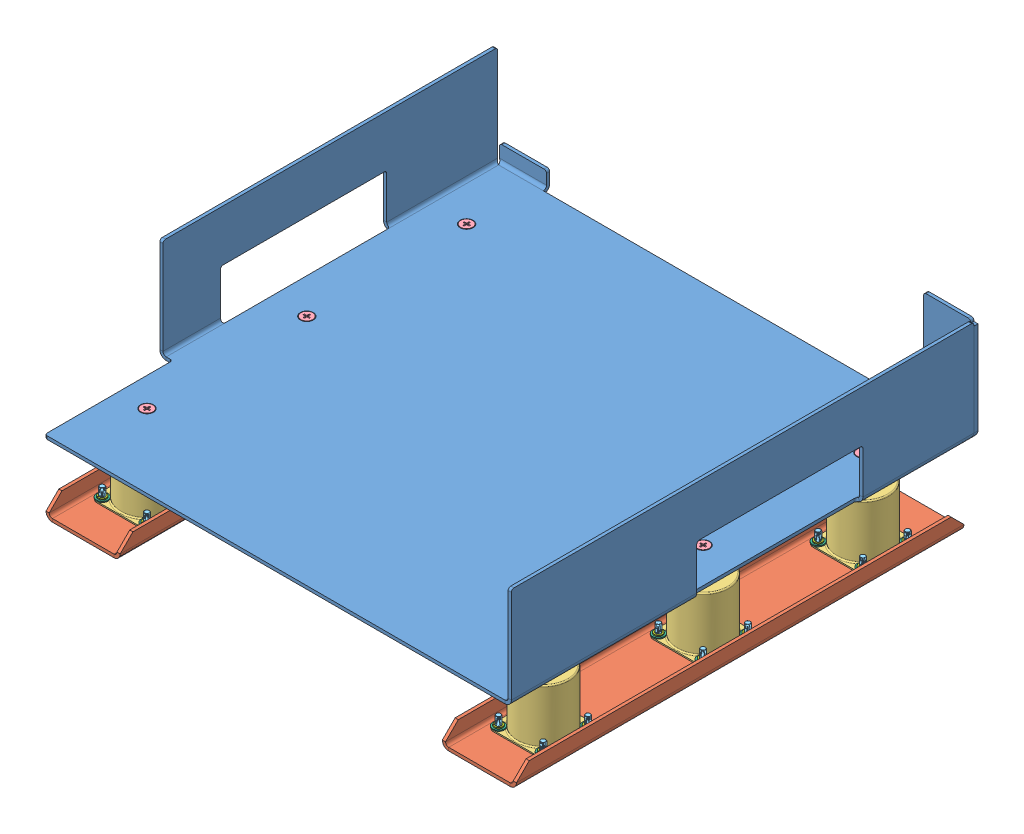
SolidWorks assembly Сборка, configuration По умолчанию. Lengths in mm.
Overall size (375.45 141.9 365.44).
87 component instances, 7 part files, 155 mates.
Components (placement in the parent):
- 1_Полка-1: 1_Полка [По умолчанию<Как обработанный>] at (-182.6691 43.1061 558.1681) size (375.45 80.44 365.44)
- 2_Основание-1: 2_Основание [По умолчанию] at (-150.1691 -18.3939 375.6681) x (0 0 -1) z (1 0 0) size (350 15 58)
- 2_Основание-2: 2_Основание [По умолчанию] at (159.8309 -18.3939 375.6681) x (0 0 1) z (-1 0 0) size (350 15 58)
- 8_Амортизатор-1: 8_Амортизатор [По умолчанию] at (-150.1691 -17.3939 500.6681) size (44 59 44)
- 8_Амортизатор-2: 8_Амортизатор [По умолчанию] at (-150.1691 -17.3939 375.6681) size (44 59 44)
- 8_Амортизатор-3: 8_Амортизатор [По умолчанию] at (159.8309 -17.3939 375.6681) size (44 59 44)
- 8_Амортизатор-4: 8_Амортизатор [По умолчанию] at (159.8309 -17.3939 250.6681) size (44 59 44)
- 8_Амортизатор-5: 8_Амортизатор [По умолчанию] at (159.8309 -17.3939 500.6681) size (44 59 44)
- 8_Амортизатор-6: 8_Амортизатор [По умолчанию] at (-150.1691 -17.3939 250.6681) size (44 59 44)
- 7_Винт_М5-1: 7_Винт_М5 [По умолчанию] at (159.8309 31.2061 250.6681) size (9.3 12.3 9.3)
- 7_Винт_М5-2: 7_Винт_М5 [По умолчанию] at (159.8309 31.2061 500.6681) size (9.3 12.3 9.3)
- 7_Винт_М5-3: 7_Винт_М5 [По умолчанию] at (159.8309 31.2061 375.6681) size (9.3 12.3 9.3)
- 7_Винт_М5-4: 7_Винт_М5 [По умолчанию] at (-150.1691 31.2061 500.6681) size (9.3 12.3 9.3)
- 7_Винт_М5-5: 7_Винт_М5 [По умолчанию] at (-150.1691 31.2061 375.6681) size (9.3 12.3 9.3)
- 7_Винт_М5-6: 7_Винт_М5 [По умолчанию] at (-150.1691 31.2061 250.6681) size (9.3 12.3 9.3)
- 6_Винт_М4-1: 6_Винт_М4 [По умолчанию] at (-132.6691 -9.2939 358.1681) x (1 0 0) z (0 0 -1) size (8.4 12.23 8.4)
- 6_Винт_М4-2: 6_Винт_М4 [По умолчанию] at (-132.6691 -9.2939 393.1681) x (1 0 0) z (0 0 -1) size (8.4 12.23 8.4)
- 6_Винт_М4-3: 6_Винт_М4 [По умолчанию] at (-132.6691 -9.2939 268.1681) x (1 0 0) z (0 0 -1) size (8.4 12.23 8.4)
- 6_Винт_М4-4: 6_Винт_М4 [По умолчанию] at (-132.6691 -9.2939 233.1681) x (1 0 0) z (0 0 -1) size (8.4 12.23 8.4)
- 6_Винт_М4-5: 6_Винт_М4 [По умолчанию] at (-167.6691 -9.2939 268.1681) x (1 0 0) z (0 0 -1) size (8.4 12.23 8.4)
- 6_Винт_М4-6: 6_Винт_М4 [По умолчанию] at (-167.6691 -9.2939 233.1681) x (1 0 0) z (0 0 -1) size (8.4 12.23 8.4)
- 6_Винт_М4-7: 6_Винт_М4 [По умолчанию] at (-167.6691 -9.2939 358.1681) x (1 0 0) z (0 0 -1) size (8.4 12.23 8.4)
- 6_Винт_М4-8: 6_Винт_М4 [По умолчанию] at (-167.6691 -9.2939 393.1681) x (1 0 0) z (0 0 -1) size (8.4 12.23 8.4)
- 6_Винт_М4-9: 6_Винт_М4 [По умолчанию] at (-132.6691 -9.2939 483.1681) x (1 0 0) z (0 0 -1) size (8.4 12.23 8.4)
- 6_Винт_М4-10: 6_Винт_М4 [По умолчанию] at (-167.6691 -9.2939 483.1681) x (1 0 0) z (0 0 -1) size (8.4 12.23 8.4)
- 6_Винт_М4-11: 6_Винт_М4 [По умолчанию] at (-132.6691 -9.2939 518.1681) x (1 0 0) z (0 0 -1) size (8.4 12.23 8.4)
- 6_Винт_М4-12: 6_Винт_М4 [По умолчанию] at (-167.6691 -9.2939 518.1681) x (1 0 0) z (0 0 -1) size (8.4 12.23 8.4)
- 6_Винт_М4-13: 6_Винт_М4 [По умолчанию] at (142.3309 -9.2939 393.1681) x (1 0 0) z (0 0 -1) size (8.4 12.23 8.4)
- 6_Винт_М4-14: 6_Винт_М4 [По умолчанию] at (177.3309 -9.2939 393.1681) x (1 0 0) z (0 0 -1) size (8.4 12.23 8.4)
- 6_Винт_М4-15: 6_Винт_М4 [По умолчанию] at (142.3309 -9.2939 358.1681) x (1 0 0) z (0 0 -1) size (8.4 12.23 8.4)
- 6_Винт_М4-16: 6_Винт_М4 [По умолчанию] at (177.3309 -9.2939 358.1681) x (1 0 0) z (0 0 -1) size (8.4 12.23 8.4)
- 6_Винт_М4-17: 6_Винт_М4 [По умолчанию] at (142.3309 -9.2939 268.1681) x (1 0 0) z (0 0 -1) size (8.4 12.23 8.4)
- 6_Винт_М4-18: 6_Винт_М4 [По умолчанию] at (177.3309 -9.2939 233.1681) x (1 0 0) z (0 0 -1) size (8.4 12.23 8.4)
- 6_Винт_М4-19: 6_Винт_М4 [По умолчанию] at (142.3309 -9.2939 233.1681) x (1 0 0) z (0 0 -1) size (8.4 12.23 8.4)
- 6_Винт_М4-20: 6_Винт_М4 [По умолчанию] at (177.3309 -9.2939 268.1681) x (1 0 0) z (0 0 -1) size (8.4 12.23 8.4)
- 6_Винт_М4-21: 6_Винт_М4 [По умолчанию] at (142.3309 -9.2939 483.1681) x (1 0 0) z (0 0 -1) size (8.4 12.23 8.4)
- 6_Винт_М4-22: 6_Винт_М4 [По умолчанию] at (142.3309 -9.2939 518.1681) x (1 0 0) z (0 0 -1) size (8.4 12.23 8.4)
- 6_Винт_М4-23: 6_Винт_М4 [По умолчанию] at (177.3309 -9.2939 518.1681) x (1 0 0) z (0 0 -1) size (8.4 12.23 8.4)
- 6_Винт_М4-24: 6_Винт_М4 [По умолчанию] at (177.3309 -9.2939 483.1681) x (1 0 0) z (0 0 -1) size (8.4 12.23 8.4)
- 5_Шайба_А4-1: 5_Шайба_А4 [По умолчанию] at (-167.6691 -17.3939 483.1681) size (9 0.8 9)
- 5_Шайба_А4-2: 5_Шайба_А4 [По умолчанию] at (-167.6691 -17.3939 518.1681) size (9 0.8 9)
- 5_Шайба_А4-3: 5_Шайба_А4 [По умолчанию] at (-132.6691 -17.3939 483.1681) size (9 0.8 9)
- 5_Шайба_А4-4: 5_Шайба_А4 [По умолчанию] at (-132.6691 -17.3939 518.1681) size (9 0.8 9)
- 5_Шайба_А4-5: 5_Шайба_А4 [По умолчанию] at (-132.6691 -17.3939 358.1681) size (9 0.8 9)
- 5_Шайба_А4-6: 5_Шайба_А4 [По умолчанию] at (-167.6691 -17.3939 358.1681) x (0.667265 0 0.74482) z (-0.74482 0 0.667265) size (9 0.8 9)
- 5_Шайба_А4-7: 5_Шайба_А4 [По умолчанию] at (-132.6691 -17.3939 393.1681) size (9 0.8 9)
- 5_Шайба_А4-8: 5_Шайба_А4 [По умолчанию] at (-167.6691 -17.3939 393.1681) x (0.975059 0 0.221947) z (-0.221947 0 0.975059) size (9 0.8 9)
- 5_Шайба_А4-9: 5_Шайба_А4 [По умолчанию] at (-167.6691 -17.3939 268.1681) size (9 0.8 9)
- 5_Шайба_А4-10: 5_Шайба_А4 [По умолчанию] at (-132.6691 -17.3939 268.1681) size (9 0.8 9)
- 5_Шайба_А4-11: 5_Шайба_А4 [По умолчанию] at (-167.6691 -17.3939 233.1681) size (9 0.8 9)
- 5_Шайба_А4-12: 5_Шайба_А4 [По умолчанию] at (-132.6691 -17.3939 233.1681) size (9 0.8 9)
- 5_Шайба_А4-13: 5_Шайба_А4 [По умолчанию] at (142.3309 -17.3939 518.1681) size (9 0.8 9)
- 5_Шайба_А4-14: 5_Шайба_А4 [По умолчанию] at (142.3309 -17.3939 483.1681) size (9 0.8 9)
- 5_Шайба_А4-15: 5_Шайба_А4 [По умолчанию] at (177.3309 -17.3939 483.1681) size (9 0.8 9)
- 5_Шайба_А4-16: 5_Шайба_А4 [По умолчанию] at (177.3309 -17.3939 518.1681) size (9 0.8 9)
- 5_Шайба_А4-17: 5_Шайба_А4 [По умолчанию] at (142.3309 -17.3939 358.1681) size (9 0.8 9)
- 5_Шайба_А4-18: 5_Шайба_А4 [По умолчанию] at (177.3309 -17.3939 393.1681) size (9 0.8 9)
- 5_Шайба_А4-19: 5_Шайба_А4 [По умолчанию] at (142.3309 -17.3939 393.1681) size (9 0.8 9)
- 5_Шайба_А4-20: 5_Шайба_А4 [По умолчанию] at (177.3309 -17.3939 358.1681) size (9 0.8 9)
- 5_Шайба_А4-21: 5_Шайба_А4 [По умолчанию] at (142.3309 -17.3939 268.1681) size (9 0.8 9)
- 5_Шайба_А4-22: 5_Шайба_А4 [По умолчанию] at (142.3309 -17.3939 233.1681) size (9 0.8 9)
- 5_Шайба_А4-23: 5_Шайба_А4 [По умолчанию] at (177.3309 -17.3939 233.1681) size (9 0.8 9)
- 5_Шайба_А4-24: 5_Шайба_А4 [По умолчанию] at (177.3309 -17.3939 268.1681) size (9 0.8 9)
- 4_Шайба-1: 4_Шайба [По умолчанию] at (-132.6691 -16.5939 518.1681) x (-0.950092 0 -0.311971) z (0.311971 0 -0.950092) size (6.5 0.8 6.5)
- 4_Шайба-2: 4_Шайба [По умолчанию] at (-167.6691 -16.5939 518.1681) x (-0.964104 0 -0.265525) z (0.265525 0 -0.964104) size (6.5 0.8 6.5)
- 4_Шайба-3: 4_Шайба [По умолчанию] at (-167.6691 -16.5939 483.1681) x (-0.900004 0 -0.435881) z (0.435881 0 -0.900004) size (6.5 0.8 6.5)
- 4_Шайба-4: 4_Шайба [По умолчанию] at (-132.6691 -16.5939 483.1681) x (0.833959 0 0.551827) z (-0.551827 0 0.833959) size (6.5 0.8 6.5)
- 4_Шайба-5: 4_Шайба [По умолчанию] at (-167.6691 -16.5939 358.1681) x (0.466083 0 -0.884741) z (0.884741 0 0.466083) size (6.5 0.8 6.5)
- 4_Шайба-6: 4_Шайба [По умолчанию] at (-132.6691 -16.5939 358.1681) x (0.892908 0 0.450239) z (-0.450239 0 0.892908) size (6.5 0.8 6.5)
- 4_Шайба-7: 4_Шайба [По умолчанию] at (-167.6691 -16.5939 393.1681) x (-0.311106 0 -0.950375) z (0.950375 0 -0.311106) size (6.5 0.8 6.5)
- 4_Шайба-8: 4_Шайба [По умолчанию] at (-132.6691 -16.5939 393.1681) size (6.5 0.8 6.5)
- 4_Шайба-13: 4_Шайба [По умолчанию] at (-132.6691 -16.5939 233.1681) size (6.5 0.8 6.5)
- 4_Шайба-14: 4_Шайба [По умолчанию] at (-167.6691 -16.5939 268.1681) size (6.5 0.8 6.5)
- 4_Шайба-15: 4_Шайба [По умолчанию] at (-132.6691 -16.5939 268.1681) x (0.985052 0 -0.172259) z (0.172259 0 0.985052) size (6.5 0.8 6.5)
- 4_Шайба-16: 4_Шайба [По умолчанию] at (-167.6691 -16.5939 233.1681) size (6.5 0.8 6.5)
- 4_Шайба-17: 4_Шайба [По умолчанию] at (177.3309 -16.5939 518.1681) x (-0.952485 0 -0.304585) z (0.304585 0 -0.952485) size (6.5 0.8 6.5)
- 4_Шайба-19: 4_Шайба [По умолчанию] at (142.3309 -16.5939 518.1681) x (-0.742093 0 -0.670297) z (0.670297 0 -0.742093) size (6.5 0.8 6.5)
- 4_Шайба-20: 4_Шайба [По умолчанию] at (142.3309 -16.5939 483.1681) x (0.157887 0 -0.987457) z (0.987457 0 0.157887) size (6.5 0.8 6.5)
- 4_Шайба-21: 4_Шайба [По умолчанию] at (177.3309 -16.5939 483.1681) x (0.73951 0 0.673145) z (-0.673145 0 0.73951) size (6.5 0.8 6.5)
- 4_Шайба-22: 4_Шайба [По умолчанию] at (177.3309 -16.5939 233.1681) x (0.8131 0 0.582125) z (-0.582125 0 0.8131) size (6.5 0.8 6.5)
- 4_Шайба-23: 4_Шайба [По умолчанию] at (142.3309 -16.5939 233.1681) size (6.5 0.8 6.5)
- 4_Шайба-24: 4_Шайба [По умолчанию] at (142.3309 -16.5939 268.1681) size (6.5 0.8 6.5)
- 4_Шайба-25: 4_Шайба [По умолчанию] at (177.3309 -16.5939 268.1681) x (-0.997954 0 -0.063934) z (0.063934 0 -0.997954) size (6.5 0.8 6.5)
- 4_Шайба-26: 4_Шайба [По умолчанию] at (142.3309 -16.5939 358.1681) size (6.5 0.8 6.5)
- 4_Шайба-27: 4_Шайба [По умолчанию] at (142.3309 -16.5939 393.1681) size (6.5 0.8 6.5)
- 4_Шайба-28: 4_Шайба [По умолчанию] at (177.3309 -16.5939 358.1681) x (0.299403 0 0.954127) z (-0.954127 0 0.299403) size (6.5 0.8 6.5)
- 4_Шайба-29: 4_Шайба [По умолчанию] at (177.3309 -16.5939 393.1681) size (6.5 0.8 6.5)
Mates (geometry in assembly coordinates):
- Концентричный1: concentric aligned: circle of 1_Полка-1; circle of 8_Амортизатор-6
- Совпадение2: coincident anti-aligned: plane of 1_Полка-1 through (-182.6691 40.6061 558.1681) normal (0 -1 0); plane of 8_Амортизатор-6 through (-150.1691 40.6061 250.6681) normal (0 1 0)
- Совпадение3: coincident aligned: cone of 1_Полка-1 through (-150.1691 40.7561 250.6681) axis (0 -1 0); cone of 7_Винт_М5-6 through (-150.1691 42.6561 250.6681) axis (0 -1 0)
- Концентричный2: concentric aligned: circle of 1_Полка-1; circle of 8_Амортизатор-2
- Совпадение4: coincident anti-aligned: plane of 1_Полка-1 through (-182.6691 40.6061 558.1681) normal (0 -1 0); plane of 8_Амортизатор-2 through (-150.1691 40.6061 375.6681) normal (0 1 0)
- Концентричный3: concentric aligned: circle of 1_Полка-1; circle of 8_Амортизатор-1
- Совпадение5: coincident anti-aligned: plane of 1_Полка-1 through (-182.6691 40.6061 558.1681) normal (0 -1 0); plane of 8_Амортизатор-1 through (-150.1691 40.6061 500.6681) normal (0 1 0)
- Концентричный4: concentric aligned: circle of 1_Полка-1; circle of 8_Амортизатор-4
- Совпадение6: coincident anti-aligned: plane of 1_Полка-1 through (-182.6691 40.6061 558.1681) normal (0 -1 0); plane of 8_Амортизатор-4 through (159.8309 40.6061 250.6681) normal (0 1 0)
- Концентричный5: concentric aligned: circle of 1_Полка-1; circle of 8_Амортизатор-3
- Совпадение7: coincident anti-aligned: plane of 1_Полка-1 through (-182.6691 40.6061 558.1681) normal (0 -1 0); plane of 8_Амортизатор-3 through (159.8309 40.6061 375.6681) normal (0 1 0)
- Концентричный6: concentric aligned: circle of 1_Полка-1; circle of 8_Амортизатор-5
- Совпадение8: coincident anti-aligned: plane of 1_Полка-1 through (-182.6691 40.6061 558.1681) normal (0 -1 0); plane of 8_Амортизатор-5 through (159.8309 40.6061 500.6681) normal (0 1 0)
- Совпадение9: coincident aligned: cone of 1_Полка-1 through (-150.1691 40.7561 375.6681) axis (0 -1 0); cone of 7_Винт_М5-5 through (-150.1691 42.6561 375.6681) axis (0 -1 0)
- Совпадение10: coincident aligned: cone of 1_Полка-1 through (-150.1691 40.7561 500.6681) axis (0 -1 0); cone of 7_Винт_М5-4 through (-150.1691 42.6561 500.6681) axis (0 -1 0)
- Совпадение11: coincident aligned: cone of 1_Полка-1 through (159.8309 40.7561 500.6681) axis (0 -1 0); cone of 7_Винт_М5-2 through (159.8309 42.6561 500.6681) axis (0 -1 0)
- Совпадение12: coincident aligned: cone of 1_Полка-1 through (159.8309 40.7561 375.6681) axis (0 -1 0); cone of 7_Винт_М5-3 through (159.8309 42.6561 375.6681) axis (0 -1 0)
- Совпадение14: coincident aligned: cone of 1_Полка-1 through (159.8309 40.7561 250.6681) axis (0 -1 0); cone of 7_Винт_М5-1 through (159.8309 42.6561 250.6681) axis (0 -1 0)
- Концентричный11: concentric aligned: circle of 2_Основание-1; circle of 8_Амортизатор-6
- Концентричный12: concentric aligned: circle of 2_Основание-1; circle of 8_Амортизатор-6
- Концентричный13: concentric aligned: circle of 2_Основание-1; circle of 8_Амортизатор-2
- Концентричный14: concentric anti-aligned: cylinder of 2_Основание-1; cylinder of 8_Амортизатор-2 through (-132.6691 24.8061 393.1681) axis (0 -1 0) radius 2
- Концентричный15: concentric anti-aligned: circle of 2_Основание-1; cylinder of 8_Амортизатор-1 through (-167.6691 24.8061 483.1681) axis (0 -1 0) radius 2
- Концентричный16: concentric aligned: circle of 2_Основание-1; circle of 8_Амортизатор-1
- Совпадение15: coincident anti-aligned: plane of 2_Основание-1 through (-150.1691 -18.3939 375.6681) normal (0 1 0); plane of 8_Амортизатор-1 through (-150.1691 -18.3939 500.6681) normal (0 -1 0)
- Совпадение16: coincident aligned: cone of 2_Основание-1 through (-167.6691 -20.8939 518.1681) axis (0 1 0); cone of 6_Винт_М4-12 through (-167.6691 -20.7939 518.1681) axis (0 1 0)
- Совпадение17: coincident aligned: cone of 2_Основание-1 through (-132.6691 -20.8939 518.1681) axis (0 1 0); cone of 6_Винт_М4-11 through (-132.6691 -20.7939 518.1681) axis (0 1 0)
- Совпадение18: coincident anti-aligned: cone of 2_Основание-1 through (-167.6691 -20.8939 483.1681) axis (0 1 0); circle of 6_Винт_М4-10
- Совпадение19: coincident anti-aligned: cone of 2_Основание-1 through (-132.6691 -20.8939 483.1681) axis (0 1 0); circle of 6_Винт_М4-9
- Совпадение20: coincident aligned: cone of 2_Основание-1 through (-167.6691 -20.8939 393.1681) axis (0 1 0); cone of 6_Винт_М4-8 through (-167.6691 -20.7939 393.1681) axis (0 1 0)
- Совпадение21: coincident aligned: cone of 2_Основание-1 through (-132.6691 -20.8939 358.1681) axis (0 1 0); cone of 6_Винт_М4-1 through (-132.6691 -20.7939 358.1681) axis (0 1 0)
- Совпадение22: coincident aligned: cone of 2_Основание-1 through (-167.6691 -20.8939 358.1681) axis (0 1 0); cone of 6_Винт_М4-7 through (-167.6691 -20.7939 358.1681) axis (0 1 0)
- Совпадение23: coincident aligned: cone of 2_Основание-1 through (-132.6691 -20.8939 393.1681) axis (0 1 0); cone of 6_Винт_М4-2 through (-132.6691 -20.7939 393.1681) axis (0 1 0)
- Совпадение24: coincident aligned: cone of 2_Основание-1 through (-167.6691 -20.8939 268.1681) axis (0 1 0); cone of 6_Винт_М4-5 through (-167.6691 -20.7939 268.1681) axis (0 1 0)
- Совпадение25: coincident aligned: cone of 2_Основание-1 through (-167.6691 -20.8939 233.1681) axis (0 1 0); cone of 6_Винт_М4-6 through (-167.6691 -20.7939 233.1681) axis (0 1 0)
- Совпадение26: coincident aligned: cone of 2_Основание-1 through (-132.6691 -20.8939 233.1681) axis (0 1 0); cone of 6_Винт_М4-4 through (-132.6691 -20.7939 233.1681) axis (0 1 0)
- Совпадение27: coincident aligned: cone of 2_Основание-1 through (-132.6691 -20.8939 268.1681) axis (0 1 0); cone of 6_Винт_М4-3 through (-132.6691 -20.7939 268.1681) axis (0 1 0)
- Концентричный17: concentric anti-aligned: circle of 2_Основание-2; cylinder of 8_Амортизатор-5 through (142.3309 24.8061 483.1681) axis (0 -1 0) radius 2
- Концентричный18: concentric anti-aligned: circle of 2_Основание-2; cylinder of 8_Амортизатор-5 through (177.3309 24.8061 518.1681) axis (0 -1 0) radius 2
- Концентричный19: concentric anti-aligned: circle of 2_Основание-2; cylinder of 8_Амортизатор-3 through (142.3309 24.8061 393.1681) axis (0 -1 0) radius 2
- Концентричный20: concentric aligned: circle of 2_Основание-2; circle of 8_Амортизатор-3
- Концентричный21: concentric anti-aligned: circle of 2_Основание-2; cylinder of 8_Амортизатор-4 through (142.3309 24.8061 268.1681) axis (0 -1 0) radius 2
- Концентричный22: concentric anti-aligned: circle of 2_Основание-2; cylinder of 8_Амортизатор-4 through (177.3309 24.8061 233.1681) axis (0 -1 0) radius 2
- Совпадение28: coincident anti-aligned: plane of 2_Основание-2 through (159.8309 -18.3939 375.6681) normal (0 1 0); plane of 8_Амортизатор-5 through (159.8309 -18.3939 500.6681) normal (0 -1 0)
- Совпадение29: coincident aligned: cone of 2_Основание-2 through (142.3309 -20.8939 518.1681) axis (0 1 0); cone of 6_Винт_М4-22 through (142.3309 -20.7939 518.1681) axis (0 1 0)
- Совпадение30: coincident aligned: cone of 2_Основание-2 through (177.3309 -20.8939 518.1681) axis (0 1 0); cone of 6_Винт_М4-23 through (177.3309 -20.7939 518.1681) axis (0 1 0)
- Совпадение31: coincident aligned: cone of 2_Основание-2 through (142.3309 -20.8939 483.1681) axis (0 1 0); cone of 6_Винт_М4-21 through (142.3309 -20.7939 483.1681) axis (0 1 0)
- Совпадение32: coincident aligned: cone of 2_Основание-2 through (177.3309 -20.8939 483.1681) axis (0 1 0); cone of 6_Винт_М4-24 through (177.3309 -20.7939 483.1681) axis (0 1 0)
- Совпадение33: coincident aligned: cone of 2_Основание-2 through (142.3309 -20.8939 393.1681) axis (0 1 0); cone of 6_Винт_М4-13 through (142.3309 -20.7939 393.1681) axis (0 1 0)
- Совпадение34: coincident aligned: cone of 2_Основание-2 through (177.3309 -20.8939 393.1681) axis (0 1 0); cone of 6_Винт_М4-14 through (177.3309 -20.7939 393.1681) axis (0 1 0)
- Совпадение35: coincident aligned: cone of 2_Основание-2 through (142.3309 -20.8939 358.1681) axis (0 1 0); cone of 6_Винт_М4-15 through (142.3309 -20.7939 358.1681) axis (0 1 0)
- Совпадение36: coincident aligned: cone of 2_Основание-2 through (177.3309 -20.8939 358.1681) axis (0 1 0); cone of 6_Винт_М4-16 through (177.3309 -20.7939 358.1681) axis (0 1 0)
- Совпадение37: coincident aligned: cone of 2_Основание-2 through (142.3309 -20.8939 268.1681) axis (0 1 0); cone of 6_Винт_М4-17 through (142.3309 -20.7939 268.1681) axis (0 1 0)
- Совпадение38: coincident aligned: cone of 2_Основание-2 through (177.3309 -20.8939 233.1681) axis (0 1 0); cone of 6_Винт_М4-18 through (177.3309 -20.7939 233.1681) axis (0 1 0)
- Совпадение39: coincident aligned: cone of 2_Основание-2 through (177.3309 -20.8939 268.1681) axis (0 1 0); cone of 6_Винт_М4-20 through (177.3309 -20.7939 268.1681) axis (0 1 0)
- Совпадение40: coincident aligned: cone of 2_Основание-2 through (142.3309 -20.8939 233.1681) axis (0 1 0); cone of 6_Винт_М4-19 through (142.3309 -20.7939 233.1681) axis (0 1 0)
- Совпадение43: coincident anti-aligned: plane of 8_Амортизатор-1 through (-150.1691 -17.3939 500.6681) normal (0 1 0); plane of 5_Шайба_А4-2 through (-167.6691 -17.3939 518.1681) normal (0 -1 0)
- Концентричный24: concentric aligned: circle of 8_Амортизатор-1; circle of 5_Шайба_А4-2
- Совпадение44: coincident anti-aligned: plane of 8_Амортизатор-1 through (-150.1691 -17.3939 500.6681) normal (0 1 0); plane of 5_Шайба_А4-4 through (-132.6691 -17.3939 518.1681) normal (0 -1 0)
- Концентричный25: concentric aligned: circle of 8_Амортизатор-1; circle of 5_Шайба_А4-4
- Совпадение45: coincident anti-aligned: plane of 8_Амортизатор-1 through (-150.1691 -17.3939 500.6681) normal (0 1 0); plane of 5_Шайба_А4-1 through (-167.6691 -17.3939 483.1681) normal (0 -1 0)
- Концентричный26: concentric aligned: circle of 8_Амортизатор-1; circle of 5_Шайба_А4-1
- Совпадение46: coincident aligned: plane of 8_Амортизатор-1 through (-150.1691 -17.3939 500.6681) normal (0 1 0); circle of 5_Шайба_А4-3
- Концентричный27: concentric aligned: circle of 8_Амортизатор-1; circle of 5_Шайба_А4-3
- Концентричный28: concentric aligned: circle of 8_Амортизатор-2; circle of 5_Шайба_А4-7
- Совпадение47: coincident anti-aligned: plane of 8_Амортизатор-2 through (-150.1691 -17.3939 375.6681) normal (0 1 0); plane of 5_Шайба_А4-7 through (-132.6691 -17.3939 393.1681) normal (0 -1 0)
- Концентричный29: concentric aligned: circle of 8_Амортизатор-2; circle of 5_Шайба_А4-8
- Совпадение49: coincident anti-aligned: plane of 8_Амортизатор-2 through (-150.1691 -17.3939 375.6681) normal (0 1 0); plane of 5_Шайба_А4-8 through (-167.6691 -17.3939 393.1681) normal (0 -1 0)
- Концентричный30: concentric aligned: circle of 8_Амортизатор-2; circle of 5_Шайба_А4-6
- Совпадение51: coincident anti-aligned: plane of 8_Амортизатор-2 through (-150.1691 -17.3939 375.6681) normal (0 1 0); plane of 5_Шайба_А4-6 through (-167.6691 -17.3939 358.1681) normal (0 -1 0)
- Концентричный31: concentric aligned: circle of 8_Амортизатор-2; circle of 5_Шайба_А4-5
- Совпадение54: coincident anti-aligned: plane of 8_Амортизатор-2 through (-150.1691 -17.3939 375.6681) normal (0 1 0); plane of 5_Шайба_А4-5 through (-132.6691 -17.3939 358.1681) normal (0 -1 0)
- Концентричный32: concentric aligned: circle of 8_Амортизатор-6; circle of 5_Шайба_А4-9
- Совпадение55: coincident anti-aligned: plane of 8_Амортизатор-6 through (-150.1691 -17.3939 250.6681) normal (0 1 0); plane of 5_Шайба_А4-9 through (-167.6691 -17.3939 268.1681) normal (0 -1 0)
- Совпадение56: coincident anti-aligned: plane of 8_Амортизатор-6 through (-150.1691 -17.3939 250.6681) normal (0 1 0); plane of 5_Шайба_А4-11 through (-167.6691 -17.3939 233.1681) normal (0 -1 0)
- Совпадение57: coincident anti-aligned: plane of 8_Амортизатор-6 through (-150.1691 -17.3939 250.6681) normal (0 1 0); plane of 5_Шайба_А4-10 through (-132.6691 -17.3939 268.1681) normal (0 -1 0)
- Совпадение58: coincident aligned: plane of 8_Амортизатор-6 through (-150.1691 -17.3939 250.6681) normal (0 1 0); circle of 5_Шайба_А4-12
- Концентричный33: concentric aligned: circle of 8_Амортизатор-6; circle of 5_Шайба_А4-12
- Концентричный34: concentric aligned: circle of 8_Амортизатор-6; circle of 5_Шайба_А4-11
- Концентричный35: concentric aligned: circle of 8_Амортизатор-6; circle of 5_Шайба_А4-10
- Совпадение59: coincident aligned: plane of 5_Шайба_А4-23 through (177.3309 -17.3939 233.1681) normal (0 -1 0); plane of 5_Шайба_А4-24 through (177.3309 -17.3939 268.1681) normal (0 -1 0)
- Совпадение60: coincident aligned: plane of 5_Шайба_А4-21 through (142.3309 -17.3939 268.1681) normal (0 -1 0); plane of 5_Шайба_А4-23 through (177.3309 -17.3939 233.1681) normal (0 -1 0)
- Совпадение61: coincident aligned: plane of 5_Шайба_А4-22 through (142.3309 -17.3939 233.1681) normal (0 -1 0); plane of 5_Шайба_А4-23 through (177.3309 -17.3939 233.1681) normal (0 -1 0)
- Совпадение62: coincident anti-aligned: plane of 8_Амортизатор-4 through (159.8309 -17.3939 250.6681) normal (0 1 0); plane of 5_Шайба_А4-23 through (177.3309 -17.3939 233.1681) normal (0 -1 0)
- Совпадение63: coincident anti-aligned: plane of 8_Амортизатор-4 through (159.8309 -17.3939 250.6681) normal (0 1 0); plane of 5_Шайба_А4-22 through (142.3309 -17.3939 233.1681) normal (0 -1 0)
- Совпадение64: coincident anti-aligned: plane of 8_Амортизатор-4 through (159.8309 -17.3939 250.6681) normal (0 1 0); plane of 5_Шайба_А4-21 through (142.3309 -17.3939 268.1681) normal (0 -1 0)
- Совпадение65: coincident anti-aligned: plane of 8_Амортизатор-4 through (159.8309 -17.3939 250.6681) normal (0 1 0); plane of 5_Шайба_А4-24 through (177.3309 -17.3939 268.1681) normal (0 -1 0)
- Концентричный36: concentric aligned: circle of 8_Амортизатор-4; circle of 5_Шайба_А4-24
- Концентричный37: concentric aligned: circle of 8_Амортизатор-4; circle of 5_Шайба_А4-21
- Концентричный38: concentric aligned: circle of 8_Амортизатор-4; circle of 5_Шайба_А4-23
- Концентричный39: concentric aligned: circle of 8_Амортизатор-4; circle of 5_Шайба_А4-22
- Совпадение66: coincident anti-aligned: plane of 8_Амортизатор-3 through (159.8309 -17.3939 375.6681) normal (0 1 0); plane of 5_Шайба_А4-18 through (177.3309 -17.3939 393.1681) normal (0 -1 0)
- Концентричный40: concentric aligned: circle of 8_Амортизатор-3; circle of 5_Шайба_А4-18
- Совпадение67: coincident anti-aligned: plane of 8_Амортизатор-3 through (159.8309 -17.3939 375.6681) normal (0 1 0); plane of 5_Шайба_А4-20 through (177.3309 -17.3939 358.1681) normal (0 -1 0)
- Концентричный41: concentric aligned: circle of 8_Амортизатор-3; circle of 5_Шайба_А4-20
- Совпадение68: coincident anti-aligned: plane of 8_Амортизатор-3 through (159.8309 -17.3939 375.6681) normal (0 1 0); plane of 5_Шайба_А4-17 through (142.3309 -17.3939 358.1681) normal (0 -1 0)
- Концентричный42: concentric aligned: circle of 8_Амортизатор-3; circle of 5_Шайба_А4-17
- Совпадение69: coincident anti-aligned: plane of 8_Амортизатор-3 through (159.8309 -17.3939 375.6681) normal (0 1 0); plane of 5_Шайба_А4-19 through (142.3309 -17.3939 393.1681) normal (0 -1 0)
- Концентричный43: concentric aligned: circle of 8_Амортизатор-3; circle of 5_Шайба_А4-19
- Совпадение70: coincident anti-aligned: plane of 8_Амортизатор-5 through (159.8309 -17.3939 500.6681) normal (0 1 0); plane of 5_Шайба_А4-15 through (177.3309 -17.3939 483.1681) normal (0 -1 0)
- Концентричный44: concentric aligned: circle of 8_Амортизатор-5; circle of 5_Шайба_А4-15
- Совпадение71: coincident anti-aligned: plane of 8_Амортизатор-5 through (159.8309 -17.3939 500.6681) normal (0 1 0); plane of 5_Шайба_А4-14 through (142.3309 -17.3939 483.1681) normal (0 -1 0)
- Концентричный45: concentric anti-aligned: circle of 8_Амортизатор-5; cylinder of 5_Шайба_А4-14 through (142.3309 -16.5939 483.1681) axis (0 -1 0) radius 2.15
- Совпадение72: coincident anti-aligned: plane of 8_Амортизатор-5 through (159.8309 -17.3939 500.6681) normal (0 1 0); plane of 5_Шайба_А4-13 through (142.3309 -17.3939 518.1681) normal (0 -1 0)
- Концентричный46: concentric aligned: circle of 8_Амортизатор-5; circle of 5_Шайба_А4-13
- Совпадение73: coincident anti-aligned: plane of 8_Амортизатор-5 through (159.8309 -17.3939 500.6681) normal (0 1 0); plane of 5_Шайба_А4-16 through (177.3309 -17.3939 518.1681) normal (0 -1 0)
- Концентричный47: concentric aligned: circle of 8_Амортизатор-5; circle of 5_Шайба_А4-16
- Совпадение74: coincident anti-aligned: plane of 5_Шайба_А4-1 through (-167.6691 -16.5939 483.1681) normal (0 1 0); plane of 4_Шайба-3 through (-167.6691 -16.5939 483.1681) normal (0 -1 0)
- Концентричный48: concentric aligned: circle of 5_Шайба_А4-1; circle of 4_Шайба-3
- Совпадение75: coincident anti-aligned: plane of 5_Шайба_А4-2 through (-167.6691 -16.5939 518.1681) normal (0 1 0); plane of 4_Шайба-2 through (-167.6691 -16.5939 518.1681) normal (0 -1 0)
- Концентричный49: concentric aligned: circle of 5_Шайба_А4-2; circle of 4_Шайба-2
- Совпадение76: coincident anti-aligned: plane of 5_Шайба_А4-4 through (-132.6691 -16.5939 518.1681) normal (0 1 0); plane of 4_Шайба-1 through (-132.6691 -16.5939 518.1681) normal (0 -1 0)
- Концентричный50: concentric aligned: circle of 5_Шайба_А4-4; circle of 4_Шайба-1
- Совпадение77: coincident anti-aligned: plane of 5_Шайба_А4-3 through (-132.6691 -16.5939 483.1681) normal (0 1 0); plane of 4_Шайба-4 through (-132.6691 -16.5939 483.1681) normal (0 -1 0)
- Концентричный51: concentric aligned: circle of 5_Шайба_А4-3; circle of 4_Шайба-4
- Совпадение78: coincident anti-aligned: plane of 5_Шайба_А4-8 through (-167.6691 -16.5939 393.1681) normal (0 1 0); plane of 4_Шайба-7 through (-167.6691 -16.5939 393.1681) normal (0 -1 0)
- Концентричный52: concentric aligned: circle of 5_Шайба_А4-8; circle of 4_Шайба-7
- Совпадение79: coincident anti-aligned: plane of 5_Шайба_А4-6 through (-167.6691 -16.5939 358.1681) normal (0 1 0); plane of 4_Шайба-5 through (-167.6691 -16.5939 358.1681) normal (0 -1 0)
- Концентричный53: concentric aligned: circle of 5_Шайба_А4-6; circle of 4_Шайба-5
- Совпадение80: coincident aligned: plane of 5_Шайба_А4-7 through (-132.6691 -16.5939 393.1681) normal (0 1 0); circle of 4_Шайба-8
- Концентричный56: concentric aligned: circle of 5_Шайба_А4-7; circle of 4_Шайба-8
- Совпадение82: coincident anti-aligned: plane of 5_Шайба_А4-5 through (-132.6691 -16.5939 358.1681) normal (0 1 0); plane of 4_Шайба-6 through (-132.6691 -16.5939 358.1681) normal (0 -1 0)
- Концентричный57: concentric aligned: circle of 5_Шайба_А4-5; circle of 4_Шайба-6
- Совпадение83: coincident anti-aligned: plane of 5_Шайба_А4-12 through (-132.6691 -16.5939 233.1681) normal (0 1 0); plane of 4_Шайба-13 through (-132.6691 -16.5939 233.1681) normal (0 -1 0)
- Концентричный58: concentric aligned: circle of 5_Шайба_А4-12; circle of 4_Шайба-13
- Совпадение84: coincident anti-aligned: plane of 5_Шайба_А4-11 through (-167.6691 -16.5939 233.1681) normal (0 1 0); plane of 4_Шайба-16 through (-167.6691 -16.5939 233.1681) normal (0 -1 0)
- Концентричный59: concentric aligned: circle of 5_Шайба_А4-11; circle of 4_Шайба-16
- Совпадение85: coincident anti-aligned: plane of 5_Шайба_А4-9 through (-167.6691 -16.5939 268.1681) normal (0 1 0); plane of 4_Шайба-14 through (-167.6691 -16.5939 268.1681) normal (0 -1 0)
- Концентричный60: concentric aligned: circle of 5_Шайба_А4-9; circle of 4_Шайба-14
- Концентричный61: concentric aligned: circle of 5_Шайба_А4-10; circle of 4_Шайба-15
- Совпадение88: coincident aligned: plane of 5_Шайба_А4-10 through (-132.6691 -16.5939 268.1681) normal (0 1 0); circle of 4_Шайба-15
- Совпадение89: coincident anti-aligned: plane of 5_Шайба_А4-13 through (142.3309 -16.5939 518.1681) normal (0 1 0); plane of 4_Шайба-19 through (142.3309 -16.5939 518.1681) normal (0 -1 0)
- Концентричный63: concentric aligned: circle of 5_Шайба_А4-13; circle of 4_Шайба-19
- Совпадение90: coincident anti-aligned: plane of 5_Шайба_А4-16 through (177.3309 -16.5939 518.1681) normal (0 1 0); plane of 4_Шайба-17 through (177.3309 -16.5939 518.1681) normal (0 -1 0)
- Концентричный64: concentric aligned: circle of 5_Шайба_А4-16; circle of 4_Шайба-17
- Совпадение91: coincident anti-aligned: plane of 5_Шайба_А4-14 through (142.3309 -16.5939 483.1681) normal (0 1 0); plane of 4_Шайба-20 through (142.3309 -16.5939 483.1681) normal (0 -1 0)
- Концентричный65: concentric aligned: circle of 5_Шайба_А4-14; circle of 4_Шайба-20
- Совпадение92: coincident anti-aligned: plane of 5_Шайба_А4-15 through (177.3309 -16.5939 483.1681) normal (0 1 0); plane of 4_Шайба-21 through (177.3309 -16.5939 483.1681) normal (0 -1 0)
- Концентричный66: concentric aligned: circle of 5_Шайба_А4-15; circle of 4_Шайба-21
- Совпадение93: coincident anti-aligned: plane of 5_Шайба_А4-21 through (142.3309 -16.5939 268.1681) normal (0 1 0); plane of 4_Шайба-24 through (142.3309 -16.5939 268.1681) normal (0 -1 0)
- Концентричный67: concentric aligned: circle of 5_Шайба_А4-21; circle of 4_Шайба-24
- Совпадение94: coincident anti-aligned: plane of 5_Шайба_А4-24 through (177.3309 -16.5939 268.1681) normal (0 1 0); plane of 4_Шайба-25 through (177.3309 -16.5939 268.1681) normal (0 -1 0)
- Концентричный68: concentric aligned: circle of 5_Шайба_А4-24; circle of 4_Шайба-25
- Совпадение95: coincident anti-aligned: plane of 5_Шайба_А4-23 through (177.3309 -16.5939 233.1681) normal (0 1 0); plane of 4_Шайба-22 through (177.3309 -16.5939 233.1681) normal (0 -1 0)
- Концентричный69: concentric aligned: circle of 5_Шайба_А4-23; circle of 4_Шайба-22
- Совпадение96: coincident anti-aligned: plane of 5_Шайба_А4-22 through (142.3309 -16.5939 233.1681) normal (0 1 0); plane of 4_Шайба-23 through (142.3309 -16.5939 233.1681) normal (0 -1 0)
- Концентричный70: concentric aligned: circle of 5_Шайба_А4-22; circle of 4_Шайба-23
- Совпадение97: coincident anti-aligned: plane of 5_Шайба_А4-17 through (142.3309 -16.5939 358.1681) normal (0 1 0); plane of 4_Шайба-26 through (142.3309 -16.5939 358.1681) normal (0 -1 0)
- Концентричный71: concentric aligned: circle of 5_Шайба_А4-17; circle of 4_Шайба-26
- Совпадение98: coincident anti-aligned: plane of 5_Шайба_А4-19 through (142.3309 -16.5939 393.1681) normal (0 1 0); plane of 4_Шайба-27 through (142.3309 -16.5939 393.1681) normal (0 -1 0)
- Концентричный72: concentric aligned: circle of 5_Шайба_А4-19; circle of 4_Шайба-27
- Совпадение99: coincident anti-aligned: plane of 5_Шайба_А4-18 through (177.3309 -16.5939 393.1681) normal (0 1 0); plane of 4_Шайба-29 through (177.3309 -16.5939 393.1681) normal (0 -1 0)
- Концентричный73: concentric aligned: circle of 5_Шайба_А4-18; circle of 4_Шайба-29
- Совпадение100: coincident anti-aligned: plane of 5_Шайба_А4-20 through (177.3309 -16.5939 358.1681) normal (0 1 0); plane of 4_Шайба-28 through (177.3309 -16.5939 358.1681) normal (0 -1 0)
- Концентричный74: concentric aligned: circle of 5_Шайба_А4-20; circle of 4_Шайба-28
